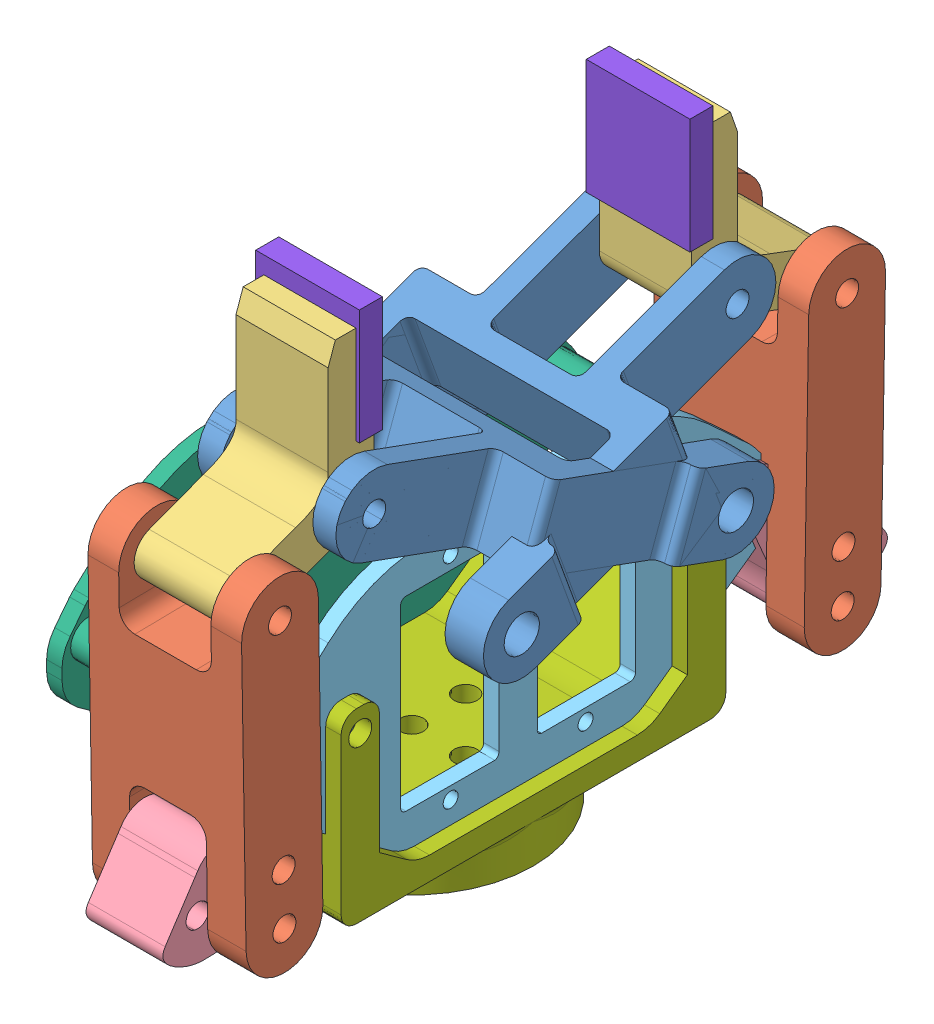
SolidWorks assembly Assemblage3, configuration Défaut. Lengths in mm.
Overall size (88.16 148.76 192.36).
14 component instances, 8 part files, 19 mates.
Components (placement in the parent):
- Pièce10-1: Pièce10 [Défaut] at (-47.5906 33.294 0.4704) x (1 0 0) z (0 0.939697 0.342009) size (74 100 20)
- Pièce11-1: Pièce11 [Défaut] at (-42.8124 14.9576 -78.3194) x (1 0 0) z (0 0.016623 0.999862) size (40 90 20)
- Pièce6-1: Pièce6 [Défaut] at (-40.3309 -110.7382 -213.3318) x (0 0.000012 1) z (-1 0 0) size (38.54 54.09 24)
- Pièce7-1: Pièce7 [Défaut] at (-41.3309 -226.6902 -33.9715) x (0 0.852367 0.522944) z (-1 0 0) size (49.2 25.36 20)
- Pièce13-1: Pièce13 [Défaut] at (-41.1709 -0.0006 0) x (0 -0.000012 -1) z (1 0 0) size (134.88 67.04 4)
- Pièce10-3: Pièce10 [Défaut] at (-47.5906 42.6909 -3.8915) x (1 0 0) z (0 -0.939689 0.342031) size (74 100 20)
- Pièce6-3: Pièce6 [Défaut] at (-52.3309 -110.7332 213.3345) x (0 -0.000012 -1) z (1 0 0) size (38.54 54.09 24)
- Pièce11-3: Pièce11 [Défaut] at (-42.8124 15.1254 68.3205) x (1 0 0) z (0 -0.016599 0.999862) size (40 90 20)
- Pièce7-3: Pièce7 [Défaut] at (-51.3309 -226.6893 33.9769) x (0 0.852354 -0.522965) z (1 0 0) size (49.2 25.36 20)
- Pièce1300-1: Pièce1300 [Défaut] at (-91.7963 0.1421 0) x (0 -0.000012 -1) z (1 0 0) size (134.88 67.04 31)
- Pièce2-1: Pièce2 [Défaut] at (-81.6609 -9.4222 0.0001) x (0 -0.000012 -1) z (1 0 0) size (100.2 58.52 63.32)
- Pièce3-1: Pièce3 [Défaut] at (-46.9559 83.7528 -44.5363) x (0 -1 0.000012) z (0 0.000012 1) size (30 27 6)
- Pièce3-2: Pièce3 [Défaut] at (-46.9559 83.7539 41.5344) x (0 -1 0.000012) z (0 0.000012 1) size (30 27 6)
- Pièce10-4: Pièce10 [Défaut] at (-47.5906 42.691 -3.8905) x (1 0 0) z (0 -0.939697 0.342009) size (74 100 20)
Mates (geometry in assembly coordinates):
- Coaxiale1: concentric anti-aligned: cylinder of Pièce10-1 through (-9.3309 56.001 -47.2992) axis (-1 0 0) radius 3; cylinder of Pièce6-1 through (-58.3309 56.001 -47.2992) axis (1 0 0) radius 2.6
- Coïncidente1: coincident anti-aligned: plane of Pièce10-1 through (-34.3309 68.818 -53.2761) normal (-1 0 0); plane of Pièce6-1 through (-34.3309 -282.3521 -370.8239) normal (1 0 0)
- Coaxiale2: concentric anti-aligned: cylinder of Pièce11-1 through (-26.3309 46.1591 -73.8374) axis (-1 0 0) radius 3; cylinder of Pièce6-1 through (-58.3309 46.1591 -73.8374) axis (1 0 0) radius 2.6
- Coïncidente2: coincident anti-aligned: plane of Pièce11-1 through (-58.3309 38.3264 -63.7058) normal (1 0 0); plane of Pièce6-1 through (-58.3309 -282.3521 -370.8239) normal (-1 0 0)
- Coïncidente3: coincident anti-aligned: plane of Pièce11-1 through (-36.3309 -33.6636 -62.509) normal (-1 0 0); plane of Pièce7-1 through (-36.3309 -438.4481 6.5433) normal (1 0 0)
- Coaxiale11: concentric anti-aligned: cylinder of Pièce7-1 through (-56.3309 4.0573 -60.4514) axis (1 0 0) radius 3; cylinder of Pièce13-1 through (-38.1709 4.0573 -60.4514) axis (-1 0 0) radius 3
- Parallèle6: parallel anti-aligned: plane of Pièce13-1 through (-42.1709 -0.4787 0) normal (-1 0 0); plane of Pièce1300-1 through (-89.4909 -0.4787 0) normal (1 0 0)
- Coaxiale18: concentric aligned: cylinder of Pièce7-3 through (-36.3309 4.0588 60.4514) axis (-1 0 0) radius 3; cylinder of Pièce1300-1 through (-89.4909 4.0588 60.4514) axis (-1 0 0) radius 3
- Coaxiale19: concentric anti-aligned: cylinder of Pièce7-1 through (-56.3309 4.0573 -60.4514) axis (1 0 0) radius 3; cylinder of Pièce1300-1 through (-89.4909 4.0573 -60.4514) axis (-1 0 0) radius 3
- Parallèle7: parallel anti-aligned: plane of Pièce6-1 through (-58.3309 -282.3483 -46.032) normal (0 0.000012 1); plane of Pièce6-3 through (-34.3309 -282.3472 46.0387) normal (0 -0.000012 -1)
- Coïncidente21: coincident anti-aligned: plane of Pièce1300-1 through (-89.4909 -34.0011 0.0004) normal (0 -1 0.000012); plane of Pièce2-1 through (-93.4909 -34.0014 -27.0592) normal (0 1 -0.000012)
- Coïncidente22: coincident anti-aligned: plane of Pièce1300-1 through (-93.4909 -0.4787 0) normal (-1 0 0); plane of Pièce2-1 through (-93.4909 -24.0008 27.06) normal (1 0 0)
- Coïncidente23: coincident anti-aligned: plane of Pièce1300-1 through (-89.4909 -36.921 -26.2268) normal (0 -0.811657 -0.584134); plane of Pièce2-1 through (-93.4909 -26.9388 -40.0972) normal (0 0.811657 0.584134)
- Coïncidente24: coincident anti-aligned: plane of Pièce6-1 through (-58.3309 68.749 -370.828) normal (0 1 -0.000012); plane of Pièce3-1 through (-60.4559 68.7529 -40.0361) normal (0 -1 0.000012)
- Coïncidente25: coincident anti-aligned: plane of Pièce6-1 through (-58.3309 -282.3483 -46.032) normal (0 0.000012 1); plane of Pièce3-1 through (-46.9559 83.7528 -46.0363) normal (0 -0.000012 -1)
- Distance1: distance = 0.875 mm aligned: plane of Pièce3-1 through (-33.4559 98.7529 -40.0365) normal (1 0 0); plane of Pièce6-1 through (-34.3309 -282.3521 -370.8239) normal (1 0 0)
- AngleLimite1: limit planar angle = 1.22173 rad aligned: plane of Pièce10-1 through (-71.3309 32.2396 -11.2521) normal (0 -0.939697 -0.342009); plane of Pièce2-1 through (-93.4909 4.5218 -50.0976) normal (0 -0.000012 -1)
- Coïncidente29: coincident anti-aligned: plane of Pièce13-1 through (-38.1709 -0.4787 0) normal (1 0 0); plane of Pièce2-1 through (-38.1709 -24.0008 27.06) normal (-1 0 0)
- Concentric4: concentric anti-aligned: cylinder of Pièce11-1 through (-26.3309 -23.8312 -72.6738) axis (-1 0 0) radius 3; cylinder of Pièce7-1 through (-56.3309 -23.8312 -72.6738) axis (1 0 0) radius 3
